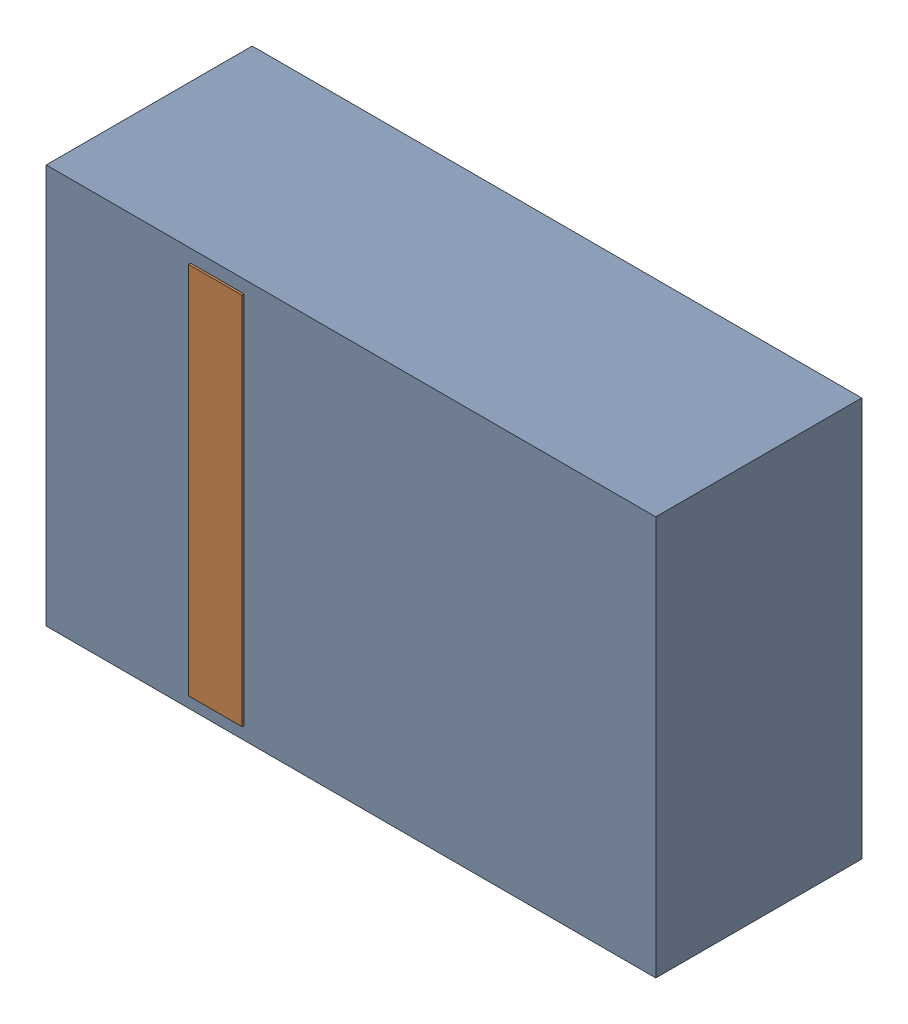
SolidWorks assembly D37, configuration Default. Lengths in mm.
Overall size (2.9 1.9 0.99).
4 component instances, 2 part files, 0 mates.
Components (placement in the parent):
- 905269392-1: 905269392 [Default] at (163.449 63.5 0) size (2.9 1.9 0.98)
  - Extruded_5-1: Extruded_5 [Default] at origin size (2.9 1.9 0.98)
- 905269800-1: 905269800 [Default] at (162.814 63.5 0.95) size (0.25 1.78 0.04)
  - Extruded_6-1: Extruded_6 [Default] at origin size (0.25 1.78 0.04)
